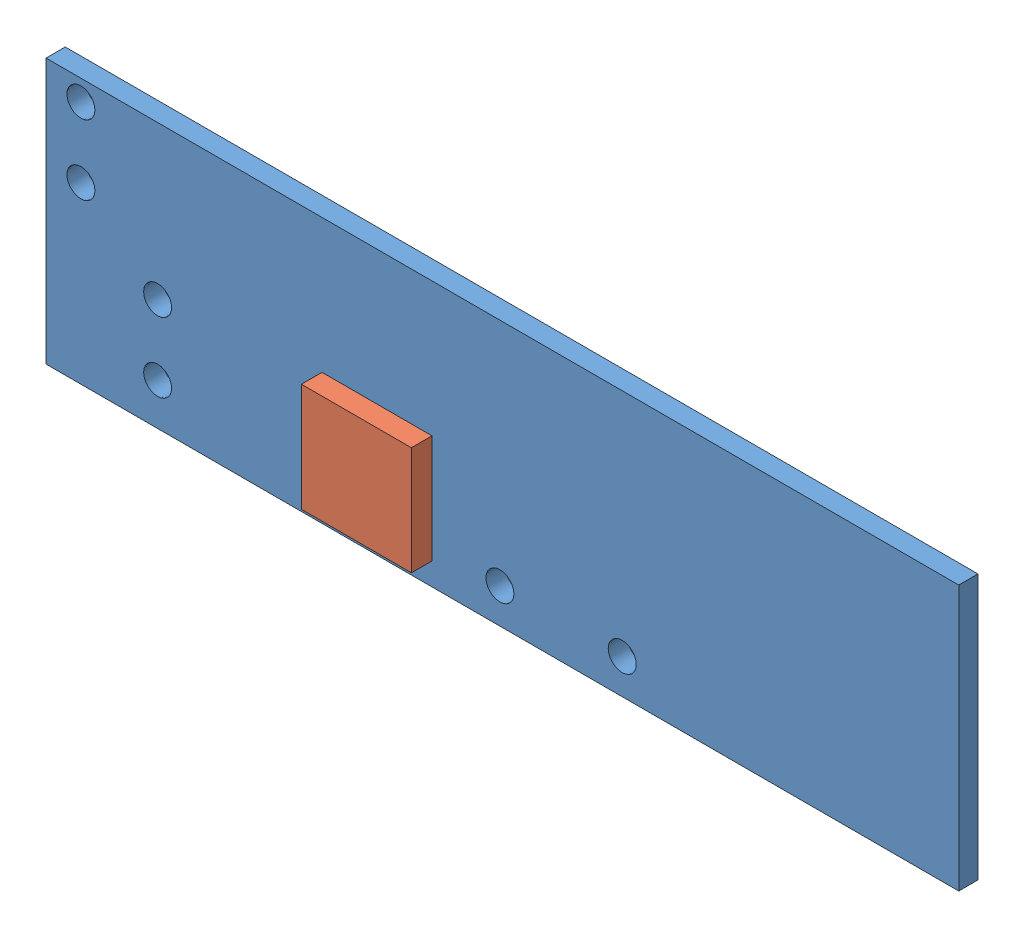
SolidWorks assembly CB, configuration Default. Lengths in mm.
Overall size (33.2 9.64 1.45).
2 component instances, 2 part files, 0 mates.
Components (placement in the parent):
- battery shield-1: battery shield [Default] at origin size (33.2 9.64 0.7)
- QFN200_QFN20_adafruit0-1: QFN200_QFN20_adafruit0 [Default] at (12.07 2.79 0.7) x (0 1 0) z (0 0 1) size (3.94 4 0.75)
